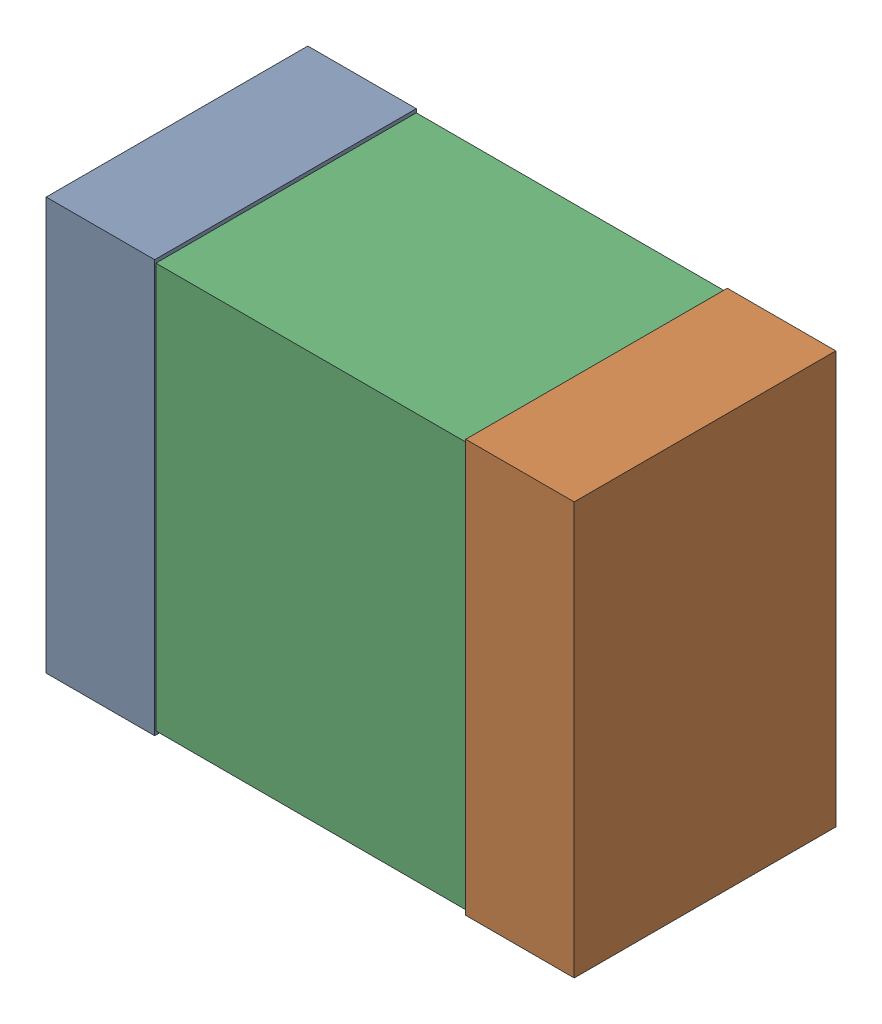
SolidWorks assembly CinB2_1Kanaloa_v2.0.0_Power, configuration Default. Lengths in mm.
Overall size (3.65 2.85 1.81).
6 component instances, 2 part files, 0 mates.
Components (placement in the parent):
- 334788400-1: 334788400 [Default] at (126.8 50.5 0) size (0.75 2.85 1.81)
  - Extruded_5-1: Extruded_5 [Default] at origin size (0.75 2.85 1.81)
- 334788400-2: 334788400 [Default] at (129.7 50.5 0) size (0.75 2.85 1.81)
  - Extruded_5-1: Extruded_5 [Default] at origin size (0.75 2.85 1.81)
- 334788784-1: 334788784 [Default] at (128.25 50.5 0) size (3.6 2.8 1.8)
  - Extruded_6-1: Extruded_6 [Default] at origin size (3.6 2.8 1.8)
